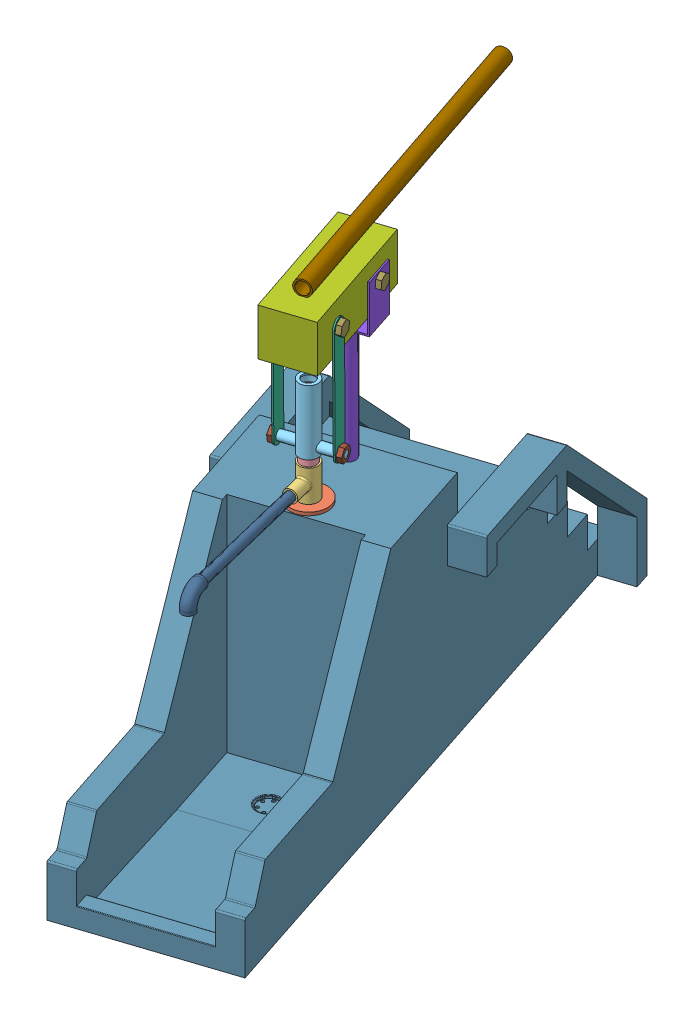
SolidWorks assembly Hand Pump Assembly, configuration Default. Lengths in mm.
Overall size (1230.04 1366.09 1938.07).
18 component instances, 14 part files, 40 mates.
Components (placement in the parent):
- Well Casing-1: Well Casing [Default] at (162.1608 -126.2885 391.9903) size (100 400 100)
- Well Seal-1: Well Seal [Default] at (162.1608 233.7115 391.9903) x (0.976215 0 0.216804) z (-0.216804 0 0.976215) size (120 50 120)
- Tee-1: Tee [Default] at (162.1608 333.7115 391.9903) x (0.237783 0 0.971318) z (-0.971318 0 0.237783) size (110 100 60)
- Guide Cylinder-1: Guide Cylinder [Default] at (162.1608 383.7115 391.9903) x (-0.833747 0 0.552147) z (-0.552147 0 -0.833747) size (50 200 50)
- Stroke Slide-1: Stroke Slide [Default] at (162.1608 506.284 391.9903) x (0.950028 0 -0.312166) z (0.312166 0 0.950028) size (190 205 60)
- Offset Link-1: Offset Link [Default] at (98.6174 405.9818 438.8628) x (0.003796 0.999926 0.011553) z (0.312143 -0.012161 0.949957) size (400 5 50)
- Offset Link-3: Offset Link [Default] at (225.5144 406.5898 344.5401) x (0.003796 0.999926 0.011553) z (-0.312143 0.012161 -0.949957) size (400 5 50)
- Pivot Block-1: Pivot Block [Default] at (132.0152 707.3717 300.2468) x (0.950028 0 -0.312166) z (0.312147 -0.01109 0.949969) size (150 150 400)
- Pivot Support-1: Pivot Support [Default] at (177.0624 658.4761 181.0668) x (-0.950028 0 0.312166) z (0 -1 0) size (160 100 1250)
- Handle-1: Handle [Default] at (-140.4182 889.5651 -529.1909) x (0.950028 0 -0.312166) z (-0.003462 -0.999939 -0.010536) size (50 1000 47.5)
- Output Pipe-1: Output Pipe [Default] at (286.4084 283.7914 899.5299) x (-0.237783 0 -0.971318) z (0.971318 0 -0.237783) size (472.53 70.01 40)
- 24MM Nut-1: 24MM Nut [Default] at (86.1586 431.284 416.9636) x (-0.098998 0.948381 -0.301286) z (0.296052 0.317133 0.900988) size (40.65 15.71 46.17)
- 24MM Nut-2: 24MM Nut [Default] at (252.4134 431.284 362.3346) x (-0.038058 0.99254 -0.115824) z (0.309837 0.121916 0.942941) size (40.65 15.71 46.17)
- 30MM Bolt-1: 30MM Bolt [Default] at (253.7421 781.2581 366.3782) x (0.097447 0.950028 0.296566) z (0.296566 -0.312166 0.902553) size (40.65 195 46.17)
- 30MM Bolt-2: 30MM Bolt [Default] at (191.3128 783.4761 176.3843) x (0.12705 0.91343 0.386657) z (0.285142 -0.406996 0.867784) size (40.65 195 46.17)
- 30MM Nut-1: 30MM Nut [Default] at (10.8075 783.4761 235.6958) x (0.277854 -0.455796 0.845604) z (0.142284 0.890084 0.433019) size (40.65 15.71 46.17)
- 30MM Nut-2: 30MM Nut [Default] at (73.2368 781.2581 425.6897) x (0.261974 -0.543799 0.797278) z (0.169755 0.839215 0.516624) size (40.65 15.71 46.17)
- Water Pump Base-2: Water Pump Base [Default] at (133.1372 -451.5285 303.6615) x (-0.312166 0 -0.950028) z (0.950028 0 -0.312166) size (1810 725.24 700)
Mates (geometry in assembly coordinates):
- Concentric1: concentric aligned: cylinder of Well Casing-1 through (162.1608 273.7115 391.9903) axis (0 -1 0) radius 50; cylinder of Well Seal-1 through (162.1608 233.7115 391.9903) axis (0 -1 0) radius 45
- Coincident1: coincident anti-aligned: plane of Well Casing-1 through (162.1608 273.7115 391.9903) normal (0 1 0); plane of Well Seal-1 through (175.169 273.7115 333.4174) normal (0 -1 0)
- Concentric2: concentric aligned: cylinder of Well Casing-1 through (162.1608 273.7115 391.9903) axis (0 -1 0) radius 50; cylinder of Tee-1 through (162.1608 383.7115 391.9903) axis (0 -1 0) radius 30
- Coincident2: coincident anti-aligned: plane of Well Seal-1 through (167.5809 283.7115 367.5849) normal (0 1 0); plane of Tee-1 through (162.1608 283.7115 391.9903) normal (0 -1 0)
- Concentric3: concentric aligned: cylinder of Tee-1 through (162.1608 383.7115 391.9903) axis (0 -1 0) radius 30; cylinder of Guide Cylinder-1 through (162.1608 583.7115 391.9903) axis (0 -1 0) radius 25
- Coincident3: coincident aligned: circle of Tee-1; circle of Guide Cylinder-1
- Concentric4: concentric aligned: cylinder of Guide Cylinder-1 through (162.1608 583.7115 391.9903) axis (0 -1 0) radius 25; cylinder of Stroke Slide-1 through (162.1608 506.284 391.9903) axis (0 -1 0) radius 30
- Concentric5: concentric anti-aligned: cylinder of Stroke Slide-1 through (233.4129 431.284 368.5779) axis (-0.950028 0 0.312166) radius 15; cylinder of Offset Link-1 through (86.1586 431.284 416.9636) axis (0.950028 0 -0.312166) radius 12
- Coincident4: coincident anti-aligned: plane of Stroke Slide-1 through (90.9087 431.284 415.4027) normal (-0.950028 0 0.312166); plane of Offset Link-1 through (98.6174 405.9818 438.8628) normal (0.950028 0 -0.312166)
- Concentric8: concentric aligned: cylinder of Stroke Slide-1 through (233.4129 431.284 368.5779) axis (-0.950028 0 0.312166) radius 15; cylinder of Offset Link-3 through (238.163 431.284 367.017) axis (-0.950028 0 0.312166) radius 12
- Coincident6: coincident aligned: plane of Stroke Slide-1 through (233.4129 431.284 368.5779) normal (0.950028 0 -0.312166); circle of Offset Link-3
- Concentric9: concentric anti-aligned: cylinder of Offset Link-1 through (87.4872 781.2581 421.0072) axis (0.950028 0 -0.312166) radius 15; cylinder of Offset Link-3 through (239.4917 781.2581 371.0607) axis (-0.950028 0 0.312166) radius 15
- Concentric10: concentric anti-aligned: cylinder of Offset Link-3 through (239.4917 781.2581 371.0607) axis (-0.950028 0 0.312166) radius 15; cylinder of Pivot Block-1 through (92.2374 781.2581 419.4463) axis (0.950028 0 -0.312166) radius 15
- Coincident7: coincident anti-aligned: plane of Offset Link-1 through (98.6174 405.9818 438.8628) normal (0.950028 0 -0.312166); plane of Pivot Block-1 through (-1.1469 859.5805 135.2458) normal (-0.950028 0 0.312166)
- Concentric11: concentric anti-aligned: cylinder of Pivot Block-1 through (29.8081 783.4761 229.4525) axis (0.950028 0 -0.312166) radius 15; cylinder of Pivot Support-1 through (177.0624 783.4761 181.0668) axis (-0.950028 0 0.312166) radius 15
- Parallel2: parallel anti-aligned: cylinder of Well Casing-1 through (162.1608 273.7115 391.9903) axis (0 -1 0) radius 50; cylinder of Pivot Support-1 through (101.0602 -441.5239 206.0401) axis (0 1 0) radius 25
- Coincident9: coincident anti-aligned: plane of Pivot Block-1 through (141.3572 859.5805 88.4209) normal (0.950028 0 -0.312166); plane of Pivot Support-1 through (156.7039 808.4761 135.1262) normal (-0.950028 0 0.312166)
- Distance4: distance = 75 mm aligned: plane of Handle-1 through (171.7283 878.4748 420.7783) normal (0.312147 -0.01109 0.949969); plane of Pivot Block-1 through (123.7117 855.1445 515.2335) normal (0.312147 -0.01109 0.949969)
- Coincident17: coincident anti-aligned: plane of Pivot Block-1 through (132.5345 857.3625 301.8272) normal (0.003462 0.999939 0.010536); plane of Handle-1 through (552.4551 842.0788 1614.3695) normal (-0.003462 -0.999939 -0.010536)
- Distance6: distance = 64 mm: line of Pivot Block-1 through (266.2158 855.1445 468.4086) axis (-0.312147 0.01109 -0.949969); line of Handle-1 through (182.0031 855.9762 417.1395) axis (-0.312147 0.01109 -0.949969)
- Concentric13: concentric anti-aligned: cylinder of Tee-1 through (181.1834 333.7115 469.6958) axis (-0.237783 0 -0.971318) radius 20; cylinder of Output Pipe-1 through (178.8056 333.7115 459.9826) axis (0.237783 0 0.971318) radius 15
- Distance7: distance = 10 mm anti-aligned: plane of Tee-1 through (181.1834 333.7115 469.6958) normal (0.237783 0 0.971318); plane of Output Pipe-1 through (178.8056 333.7115 459.9826) normal (-0.237783 0 -0.971318)
- Parallel3: parallel anti-aligned: plane of Well Seal-1 through (167.5809 283.7115 367.5849) normal (0 1 0); plane of Output Pipe-1 through (286.4084 283.7914 899.5299) normal (0 -1 0)
- Concentric15: concentric anti-aligned: circle of Stroke Slide-1; circle of 24MM Nut-1
- Concentric16: concentric anti-aligned: circle of Stroke Slide-1; circle of 24MM Nut-2
- Coincident22: coincident anti-aligned: plane of Offset Link-1 through (93.8672 405.9818 440.4237) normal (-0.950028 0 0.312166); plane of 24MM Nut-1 through (86.1586 431.284 416.9636) normal (0.950028 0 -0.312166)
- Coincident24: coincident anti-aligned: plane of Offset Link-3 through (230.2645 406.5898 342.9793) normal (0.950028 0 -0.312166); plane of 24MM Nut-2 through (238.163 431.284 367.017) normal (-0.950028 0 0.312166)
- Concentric17: concentric anti-aligned: cylinder of Offset Link-3 through (239.4917 781.2581 371.0607) axis (-0.950028 0 0.312166) radius 15; cylinder of 30MM Bolt-1 through (68.4867 781.2581 427.2505) axis (0.950028 0 -0.312166) radius 15
- Coincident25: coincident anti-aligned: plane of Offset Link-3 through (230.2645 406.5898 342.9793) normal (0.950028 0 -0.312166); plane of 30MM Bolt-1 through (239.4917 781.2581 371.0607) normal (-0.950028 0 0.312166)
- Concentric18: concentric anti-aligned: cylinder of Pivot Support-1 through (177.0624 783.4761 181.0668) axis (-0.950028 0 0.312166) radius 15; cylinder of 30MM Bolt-2 through (6.0574 783.4761 237.2566) axis (0.950028 0 -0.312166) radius 15
- Coincident26: coincident anti-aligned: plane of Pivot Support-1 through (161.4541 658.4761 133.5654) normal (0.950028 0 -0.312166); plane of 30MM Bolt-2 through (177.0624 783.4761 181.0668) normal (-0.950028 0 0.312166)
- Concentric19: concentric anti-aligned: circle of 30MM Bolt-2; circle of 30MM Nut-1
- Coincident27: coincident anti-aligned: plane of Pivot Support-1 through (9.4497 658.4761 183.5119) normal (-0.950028 0 0.312166); plane of 30MM Nut-1 through (25.0579 783.4761 231.0133) normal (0.950028 0 -0.312166)
- Concentric20: concentric anti-aligned: circle of 30MM Bolt-1; circle of 30MM Nut-2
- Coincident28: coincident anti-aligned: plane of Offset Link-1 through (93.8672 405.9818 440.4237) normal (-0.950028 0 0.312166); plane of 30MM Nut-2 through (87.4872 781.2581 421.0072) normal (0.950028 0 -0.312166)
- LimitDistance1: limit distance = 22.5725 mm anti-aligned: plane of Tee-1 through (162.1608 383.7115 391.9903) normal (0 1 0); plane of Stroke Slide-1 through (185.9115 406.284 384.1862) normal (0 -1 0)
- Lock3: lock: unknown of Tee-1; unknown of Pivot Support-1
- Parallel4: parallel anti-aligned: line of Pivot Support-1 through (161.4541 658.4761 133.5654) axis (0.312166 0 0.950028); line of Water Pump Base-2 through (425.8693 273.7115 393.6893) axis (-0.312166 0 -0.950028)
- Coincident30: coincident anti-aligned: cylinder of Well Casing-1 through (162.1608 273.7115 391.9903) axis (0 -1 0) radius 50; circle of Water Pump Base-2
- Coincident31: coincident anti-aligned: plane of Well Seal-1 through (175.169 273.7115 333.4174) normal (0 -1 0); plane of Water Pump Base-2 through (133.1372 273.7115 303.6615) normal (0 1 0)
